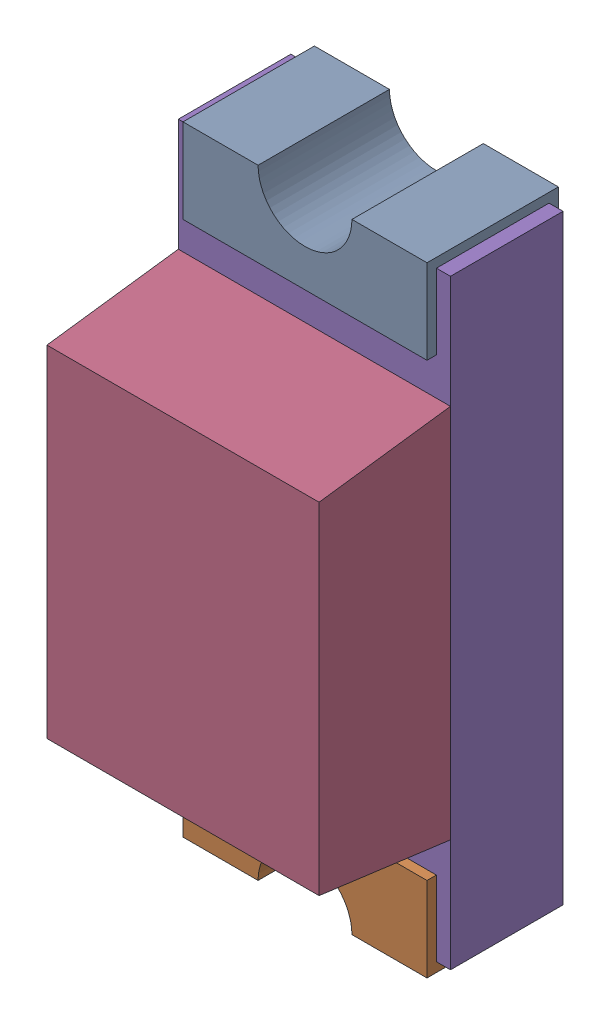
SolidWorks assembly P4, configuration Standard. Lengths in mm.
Overall size (0.73 1.65 0.68).
6 component instances, 5 part files, 0 mates.
Components (placement in the parent):
- P4-subassembly-1-1: P4-subassembly-1 [Standard] at (-15.4999 -2.5501 0) x (1 0 0) z (0 0 1) size (0.72 1.65 0.68)
  - User Library-LED SMD0603-1: User Library-LED SMD0603 [Standard] at origin size (0.65 0.28 0.35)
  - User Library-LED SMD0603-1-1: User Library-LED SMD0603-1 [Standard] at origin size (0.65 0.28 0.35)
  - User Library-LED SMD0603-2-1: User Library-LED SMD0603-2 [Standard] at origin size (0.15 0.16 0.07)
  - User Library-LED SMD0603-3-1: User Library-LED SMD0603-3 [Standard] at origin size (0.72 1 0.35)
  - User Library-LED SMD0603-4-1: User Library-LED SMD0603-4 [Standard] at origin size (0.72 1.6 0.3)
